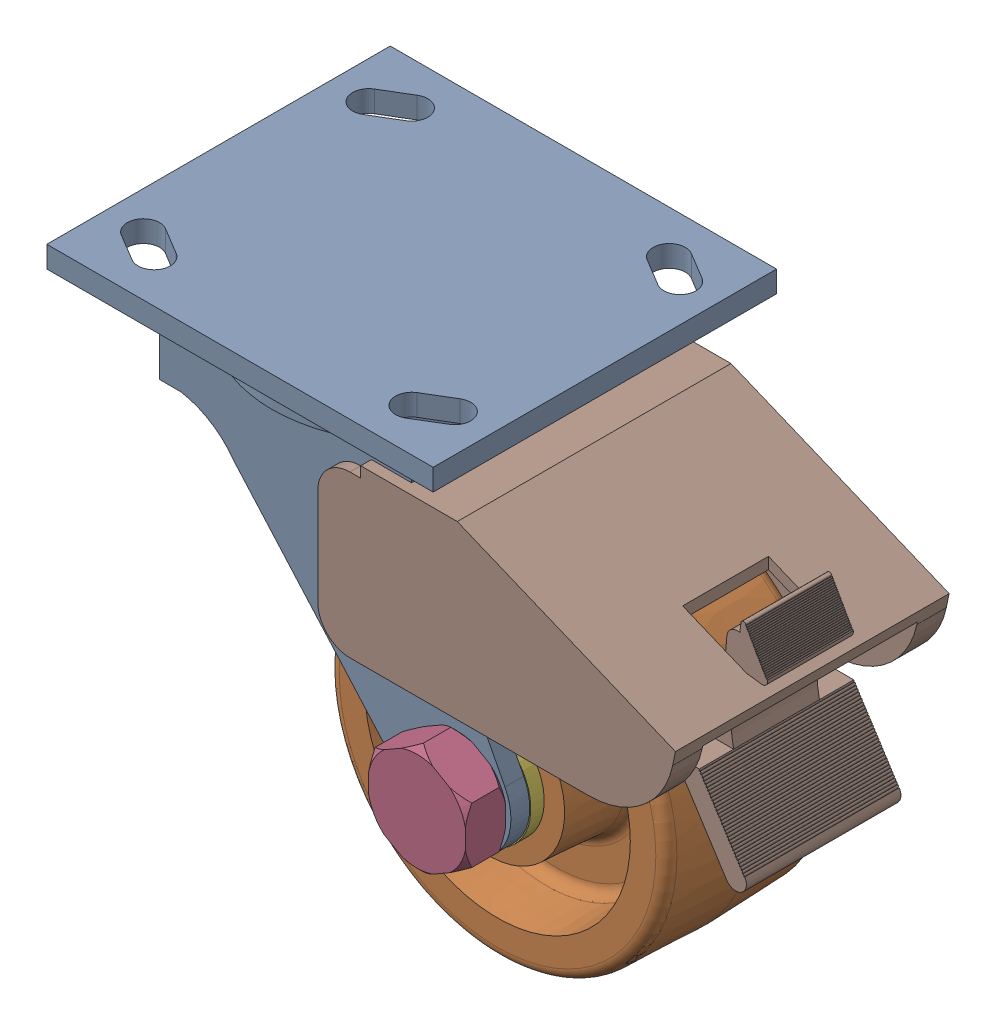
SolidWorks assembly Montagem1, configuration Valor predeterminado. Lengths in mm.
Overall size (213.35 172.07 101.6).
8 component instances, 7 part files, 0 mates.
Components (placement in the parent):
- S-BC-4AZ1-1: S-BC-4AZ1 [Valor predeterminado] at origin size (123.83 107.95 101.6)
- W-420-AZ-3_4p-1: W-420-AZ-3_4p [Valor predeterminado] at (107.95 -85.725 0) x (0 0 -1) z (-1 0 0) size (55.56 101.6 101.6)
- DELRIN-4-2-1: DELRIN-4-2 [Valor predeterminado] at (107.95 -85.725 -27.7812) x (0 0 1) z (-1 0 0) size (55.56 30.16 30.16)
- S-3_4-3_59375-1: S-3_4-3_59375 [Valor predeterminado] at (107.95 -85.725 37.3126) x (0 0 -1) z (-1 0 0) size (97.95 33 28.57)
- N-3_4-1: N-3_4 [Valor predeterminado] at (107.95 -85.725 -37.3126) x (0 0 -1) z (-1 0 0) size (10.72 33 28.57)
- W-3_4-0_3125-1: W-3_4-0_3125 [Valor predeterminado] at (107.95 -85.725 31.75) x (0 0 1) z (-1 0 0) size (7.94 32.38 32.38)
- W-3_4-0_3125-2: W-3_4-0_3125 [Valor predeterminado] at (107.95 -85.725 -31.75) x (0 0 -1) z (-1 0 0) size (7.94 32.38 32.38)
- S-BC-4AZ11-1: S-BC-4AZ11 [Valor predeterminado] at origin size (109.19 71.09 80.98)
